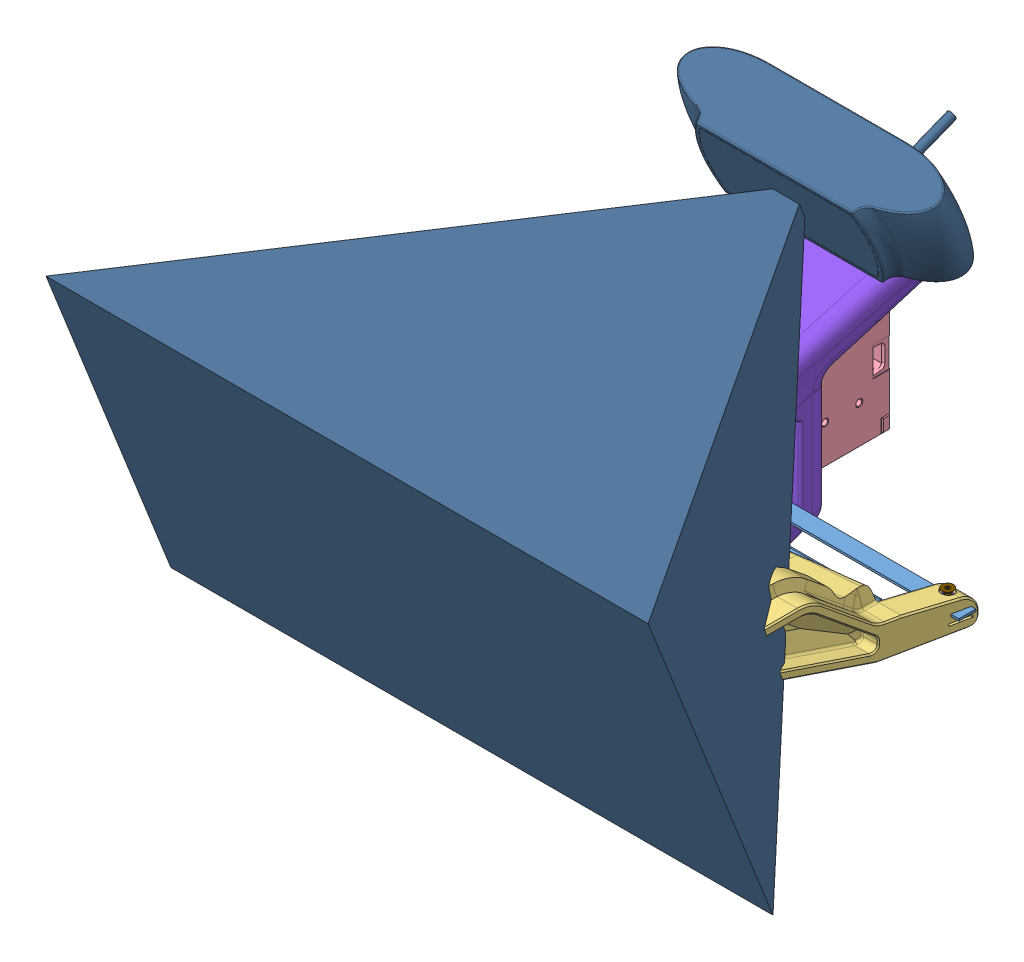
SolidWorks assembly OpenGrip_Assy, configuration Default. Lengths in mm.
Overall size (168.5 132.23 164.7).
65 component instances, 20 part files, 137 mates.
Components (placement in the parent):
- OpenGrip_Master-2: OpenGrip_Master [Default] at origin (suppressed, hidden)
- MGN7_Rail-1: MGN7_Rail [80mm] at (21.75 9 42.45) x (0 1 0) z (-1 0 0) size (7 4.8 80)
- MGN7_Rail-2: MGN7_Rail [80mm] at (78.25 -9 42.45) x (0 1 0) z (-1 0 0) size (7 4.8 80)
- MGN7C_Carriage-1: MGN7C_Carriage [Default] at (0 9 40) x (0 -1 0) z (1 0 0) size (17 6.5 23.48)
- MGN7C_Carriage-2: MGN7C_Carriage [Default] at (0 -9 40) x (0 -1 0) z (1 0 0) size (17 6.5 23.48)
- Gripper_Jaw-1: Gripper_Jaw [Default] at (0 0 0.1) size (101.38 32.39 102.84)
- Gripper_Jaw-2: Gripper_Jaw [Default] at (0 0 0.1) x (-1 0 0) z (0 0 1) size (101.38 32.39 102.84)
- XL-430-1: XL-430 [Default] x (-1 0 0) z (0 0 1) size (28.5 46.5 34)
- 430_Horn-1: 430_Horn [Default] at (0 0 0.25) x (-0.999988 0.004902 0) z (0 0 1) size (20.5 20.5 4.15)
- Gripper_Carriage_Mount-1: Gripper_Carriage_Mount [Default] at origin size (34.5 55.1 3.17)
- Gripper_Drive_Pulley-1: Gripper_Drive_Pulley [Default] x (-0.999864 -0.016494 0) z (0 0 1) size (27 27 12.75)
- Gripper_Structure-1: Gripper_Structure [Default] at origin size (59.8 80.24 58.54)
- CF_Spring_Idler-1: CF_Spring_Idler [Default] at (-19.402 17.1492 0) x (0.122802 -0.992431 0) z (0 0 1) size (9.1 9.1 8.94)
- CF_Spring_Idler-2: CF_Spring_Idler [Default] at (-7.4466 -37.6262 0) x (0.924615 -0.380902 0) z (0 0 1) size (9.1 9.1 8.94)
- C922X_Pro-1: C922X_Pro [Tilted Down] at (-0.0197 67.744 0.4358) x (1 0 0) z (0 0.110801 0.993843) size (211.74 160.55 195.68)
- CF_Spring_Idler_Cap-1: CF_Spring_Idler_Cap [Default] at origin size (9.1 9.1 1)
- CF_Spring_Idler_Cap-2: CF_Spring_Idler_Cap [Default] at (0 -39.1 0) size (9.1 9.1 1)
- 0.1x8x110_CF-2: 0.1x8x110_CF [9293K111] at (0 -19.55 28.4812) x (0 0 1) z (0 1 0) size (8.01 10.11 7.57)
- 0.1x8x110_CF-1: 0.1x8x110_CF [9293K111] at (0 19.55 28.4812) x (0 0 1) z (0 -1 0) size (8.01 10.11 7.57)
- 91292A831_18-8 Stainless Steel Socket Head Screw-1: 91292A831_18-8 Stainless Steel Socket Head Screw [91292A831] at (58.25 -9 48.35) x (-0.599094 -0.800678 0) z (0 0 1) size (3.8 3.8 8.1)
- 92125A051_18-8 Stainless Steel Hex Drive Flat Head Screw-1: 92125A051_18-8 Stainless Steel Hex Drive Flat Head Screw [92125A051] at (-4 15 36.215) x (-1 0 0) z (0 0 -1) size (4 4 5.21)
- 92125A059_18-8 Stainless Steel Hex Drive Flat Head Screw-1: 92125A059_18-8 Stainless Steel Hex Drive Flat Head Screw [92125A059] at (0 19.55 28.61) size (4 4 16.28)
- 92125A059_18-8 Stainless Steel Hex Drive Flat Head Screw-2: 92125A059_18-8 Stainless Steel Hex Drive Flat Head Screw [92125A059] at (0 -19.55 28.61) x (0.987351 0.158553 0) z (0 0 1) size (4 4 16.28)
- 92000A108_Passivated 18-8 Stainless Steel Pan Head Phillips Screws-1: 92000A108_Passivated 18-8 Stainless Steel Pan Head Phillips Screws [92000A108] at (-11 32 12.45) x (0.327132 -0.944979 0) z (0 0 1) size (5 5 16.27)
- 92000A108_Passivated 18-8 Stainless Steel Pan Head Phillips Screws-2: 92000A108_Passivated 18-8 Stainless Steel Pan Head Phillips Screws [92000A108] at (11 32 12.45) x (-0.176447 -0.98431 0) z (0 0 1) size (5 5 16.27)
- 92000A108_Passivated 18-8 Stainless Steel Pan Head Phillips Screws-4: 92000A108_Passivated 18-8 Stainless Steel Pan Head Phillips Screws [92000A108] at (-11 -8 12.45) x (-0.17128 0.985222 0) z (0 0 1) size (5 5 16.27)
- 92000A108_Passivated 18-8 Stainless Steel Pan Head Phillips Screws-6: 92000A108_Passivated 18-8 Stainless Steel Pan Head Phillips Screws [92000A108] at (11.1653 -8.1875 12.45) x (-0.186548 -0.982446 0) z (0 0 1) size (5 5 16.27)
- M2_Heatset-1: M2_Heatset [94180A307] at (-1.75 -9 46.31) x (-0.923728 -0.383049 0) z (0 0 -1) size (3.58 3.58 3.07)
- M2_Heatset-2: M2_Heatset [94180A307] at (13.25 -9 46.31) x (-0.85131 -0.524663 0) z (0 0 -1) size (3.58 3.58 3.07)
- M2_Heatset-3: M2_Heatset [94180A307] at (28.25 -9 46.31) x (-0.777574 -0.628792 0) z (0 0 -1) size (3.58 3.58 3.07)
- M2_Heatset-4: M2_Heatset [94180A307] at (43.25 -9 46.31) x (-0.715577 -0.698533 0) z (0 0 -1) size (3.58 3.58 3.07)
- M2_Heatset-5: M2_Heatset [94180A307] at (58.25 -9 46.31) x (-0.676489 -0.736453 0) z (0 0 -1) size (3.58 3.58 3.07)
- M2_Heatset-8: M2_Heatset [94180A307] at (-58.25 9 46.31) x (-0.669293 -0.742999 0) z (0 0 -1) size (3.58 3.58 3.07)
- M2_Heatset-10: M2_Heatset [94180A307] at (-43.25 9 46.31) x (-0.699005 -0.715117 0) z (0 0 -1) size (3.58 3.58 3.07)
- M2_Heatset-12: M2_Heatset [94180A307] at (-28.25 9 46.31) x (-0.762825 -0.646605 0) z (0 0 -1) size (3.58 3.58 3.07)
- M2_Heatset-14: M2_Heatset [94180A307] at (-13.25 9 46.31) x (-0.845962 -0.533243 0) z (0 0 -1) size (3.58 3.58 3.07)
- M2_Heatset-16: M2_Heatset [94180A307] at (1.75 9 46.31) x (-0.923728 -0.383049 0) z (0 0 -1) size (3.58 3.58 3.07)
- 91292A831_18-8 Stainless Steel Socket Head Screw-3: 91292A831_18-8 Stainless Steel Socket Head Screw [91292A831] at (43.25 -9 48.35) x (0.684483 -0.729029 0) z (0 0 1) size (3.8 3.8 8.1)
- 91292A831_18-8 Stainless Steel Socket Head Screw-5: 91292A831_18-8 Stainless Steel Socket Head Screw [91292A831] at (28.25 -9 48.35) x (0.547489 -0.836813 0) z (0 0 1) size (3.8 3.8 8.1)
- 91292A831_18-8 Stainless Steel Socket Head Screw-7: 91292A831_18-8 Stainless Steel Socket Head Screw [91292A831] at (13.25 -9 48.35) x (0.393861 -0.91917 0) z (0 0 1) size (3.8 3.8 8.1)
- 91292A831_18-8 Stainless Steel Socket Head Screw-9: 91292A831_18-8 Stainless Steel Socket Head Screw [91292A831] at (-1.75 -9 48.35) x (0.228265 -0.973599 0) z (0 0 1) size (3.8 3.8 8.1)
- 91292A831_18-8 Stainless Steel Socket Head Screw-11: 91292A831_18-8 Stainless Steel Socket Head Screw [91292A831] at (1.75 9 48.35) x (0.055733 -0.998446 0) z (0 0 1) size (3.8 3.8 8.1)
- 91292A831_18-8 Stainless Steel Socket Head Screw-13: 91292A831_18-8 Stainless Steel Socket Head Screw [91292A831] at (-13.25 9 48.35) x (-0.118492 -0.992955 0) z (0 0 1) size (3.8 3.8 8.1)
- 91292A831_18-8 Stainless Steel Socket Head Screw-15: 91292A831_18-8 Stainless Steel Socket Head Screw [91292A831] at (-28.25 9 48.35) x (-0.289116 -0.957294 0) z (0 0 1) size (3.8 3.8 8.1)
- 91292A831_18-8 Stainless Steel Socket Head Screw-17: 91292A831_18-8 Stainless Steel Socket Head Screw [91292A831] at (-43.25 9 48.35) x (-0.450956 -0.892546 0) z (0 0 1) size (3.8 3.8 8.1)
- 91292A831_18-8 Stainless Steel Socket Head Screw-19: 91292A831_18-8 Stainless Steel Socket Head Screw [91292A831] at (-58.25 9 48.35) x (-0.599094 -0.800678 0) z (0 0 1) size (3.8 3.8 8.1)
- M2_Heatset-18: M2_Heatset [94180A307] at (-77.9377 7.46 26.6) x (0.982823 0 0.184551) z (0 -1 0) size (3.58 3.58 3.07)
- 92125A054_18-8 Stainless Steel Hex Drive Flat Head Screw-1: 92125A054_18-8 Stainless Steel Hex Drive Flat Head Screw [92125A054] at (-77.9377 8.125 26.6) x (1 0 0) z (0 -1 0) size (4 4 8.23)
- M2_Heatset-19: M2_Heatset [94180A307] at (77.9377 -7.46 26.6) x (0.184551 0 0.982823) z (0 1 0) size (3.58 3.58 3.07)
- 92125A054_18-8 Stainless Steel Hex Drive Flat Head Screw-2: 92125A054_18-8 Stainless Steel Hex Drive Flat Head Screw [92125A054] at (77.9377 -8.125 26.6) x (0 0 1) z (0 1 0) size (4 4 8.23)
- M2_Heatset-21: M2_Heatset [94180A307] at (14.75 13.04 28.5813) x (0.366462 0 0.930433) z (0 1 0) size (3.58 3.58 3.07)
- 92125A054_18-8 Stainless Steel Hex Drive Flat Head Screw-4: 92125A054_18-8 Stainless Steel Hex Drive Flat Head Screw [92125A054] at (14.75 11.5 28.5813) x (0 0 1) z (0 1 0) size (4 4 8.23)
- M2_Heatset-23: M2_Heatset [94180A307] at (-14.75 -13.04 28.5813) x (0.930433 0 0.366462) z (0 -1 0) size (3.58 3.58 3.07)
- 92125A054_18-8 Stainless Steel Hex Drive Flat Head Screw-5: 92125A054_18-8 Stainless Steel Hex Drive Flat Head Screw [92125A054] at (-14.75 -11.5 28.5813) x (1 0 0) z (0 -1 0) size (4 4 8.23)
- 92125A054_18-8 Stainless Steel Hex Drive Flat Head Screw-7: 92125A054_18-8 Stainless Steel Hex Drive Flat Head Screw [92125A054] at (-12.25 22.55 32.61) x (0 -1 0) z (0 0 1) size (4 4 8.23)
- M2_Heatset-25: M2_Heatset [94180A307] at (0 -19.55 21.9275) x (-0.719094 -0.694913 0) z (0 0 1) size (3.58 3.58 3.07)
- M2_Heatset-26: M2_Heatset [94180A307] at (-12.25 -22.55 32.115) x (-0.599818 -0.800137 0) z (0 0 1) size (3.58 3.58 3.07)
- M2_Heatset-28: M2_Heatset [94180A307] at (12.25 -22.55 32.115) x (-0.493052 -0.87 0) z (0 0 1) size (3.58 3.58 3.07)
- M2_Heatset-30: M2_Heatset [94180A307] at (0 19.55 21.9275) x (-0.409811 -0.91217 0) z (0 0 1) size (3.58 3.58 3.07)
- M2_Heatset-32: M2_Heatset [94180A307] at (-12.25 22.55 32.115) x (-0.359546 -0.933127 0) z (0 0 1) size (3.58 3.58 3.07)
- M2_Heatset-34: M2_Heatset [94180A307] at (12.25 22.55 32.115) x (-0.350452 -0.936581 0) z (0 0 1) size (3.58 3.58 3.07)
- 92125A054_18-8 Stainless Steel Hex Drive Flat Head Screw-8: 92125A054_18-8 Stainless Steel Hex Drive Flat Head Screw [92125A054] at (12.25 22.55 32.61) x (0.158553 -0.987351 0) z (0 0 1) size (4 4 8.23)
- 92125A054_18-8 Stainless Steel Hex Drive Flat Head Screw-10: 92125A054_18-8 Stainless Steel Hex Drive Flat Head Screw [92125A054] at (12.25 -22.55 32.61) x (0.282984 -0.959125 0) z (0 0 1) size (4 4 8.23)
- 92125A054_18-8 Stainless Steel Hex Drive Flat Head Screw-12: 92125A054_18-8 Stainless Steel Hex Drive Flat Head Screw [92125A054] at (-12.25 -22.55 32.61) x (0.371154 -0.928571 0) z (0 0 1) size (4 4 8.23)
- Drive Belt-1: Drive Belt [Default] at (1.3318 1.3765 0.1) x (0.999864 0.016494 0) z (0 0 1) size (166.7 24.25 6)
Mates (geometry in assembly coordinates):
- Width1: width anti-aligned: plane of MGN7C_Carriage-1 through (6.75 12.5 40) normal (0 -1 0); plane of MGN7_Rail-1 through (6.75 5.5 40) normal (0 1 0); plane of MGN7C_Carriage-1 through (-78.25 12.5 40.7563) normal (0 1 0); plane of MGN7_Rail-1 through (-78.25 5.5 40.7563) normal (0 -1 0)
- Coincident7: coincident anti-aligned: plane of MGN7_Rail-1 through (-78.25 5.7 40.05) normal (0 0 -1); plane of MGN7C_Carriage-1 through (6.75 9 40.05) normal (0 0 1)
- Coincident8: coincident: line of OpenGrip_Master-2 through (-11.25 17.5 36.75) axis (0 -1 0); plane of MGN7C_Carriage-1 through (-11.25 9 40) normal (-1 0 0)
- Coincident9: coincident anti-aligned: plane of OpenGrip_Master-2 through (0 0 36.75) normal (0 0 1); plane of MGN7C_Carriage-1 through (6.75 9 36.75) normal (0 0 -1)
- Coincident11: coincident: line of OpenGrip_Master-2 through (11.25 17.5 36.75) axis (-1 0 0); plane of MGN7C_Carriage-1 through (6.75 17.5 40) normal (0 1 0)
- Coincident12: coincident: line of OpenGrip_Master-2 through (-11.25 -17.5 36.75) axis (1 0 0); plane of MGN7C_Carriage-2 through (6.75 -17.5 40) normal (0 -1 0)
- Coincident13: coincident: line of OpenGrip_Master-2 through (11.25 -0.5 36.75) axis (0 -1 0); plane of MGN7C_Carriage-2 through (11.25 -9 40) normal (1 0 0)
- Coincident14: coincident anti-aligned: plane of OpenGrip_Master-2 through (0 0 36.75) normal (0 0 1); plane of MGN7C_Carriage-2 through (6.75 -9 36.75) normal (0 0 -1)
- Coincident15: coincident anti-aligned: plane of MGN7_Rail-2 through (-21.75 -12.3 40.05) normal (0 0 -1); plane of MGN7C_Carriage-2 through (6.75 -9 40.05) normal (0 0 1)
- Width2: width anti-aligned: plane of MGN7_Rail-2 through (-21.75 -12.5 40.7563) normal (0 -1 0); plane of MGN7C_Carriage-2 through (-21.75 -5.5 40.7563) normal (0 1 0); plane of MGN7_Rail-2 through (6.75 -12.5 40) normal (0 1 0); plane of MGN7C_Carriage-2 through (6.75 -5.5 40) normal (0 -1 0)
- Linear/Linear Coupler1: linear coupler = 0.001 : 0.001 mm: plane of MGN7_Rail-1 through (-68.25 5.5 44.85) normal (-1 0 0); plane of MGN7_Rail-2 through (68.25 -12.5 44.85) normal (1 0 0)
- Coincident35: coincident anti-aligned: plane of MGN7_Rail-1 through (11.75 5.5 44.85) normal (1 0 0); plane of Gripper_Jaw-1 through (11.75 0 31.32) normal (-1 0 0)
- Coincident36: coincident anti-aligned: plane of MGN7_Rail-1 through (-78.25 5.7 44.85) normal (0 0 1); plane of Gripper_Jaw-1 through (-69 0 44.85) normal (0 0 -1)
- Coincident37: coincident anti-aligned: plane of MGN7_Rail-2 through (-11.75 -12.5 44.85) normal (-1 0 0); plane of Gripper_Jaw-2 through (-11.75 0 31.32) normal (1 0 0)
- Coincident38: coincident anti-aligned: plane of MGN7_Rail-2 through (-21.75 -12.3 44.85) normal (0 0 1); plane of Gripper_Jaw-2 through (69 0 44.85) normal (0 0 -1)
- Concentric3: concentric anti-aligned: line of XL-430-1 through (0 0 18.8501) axis (0 0 -1); cylinder of 430_Horn-1 through (0 0 15.75) axis (0 0 1) radius 10.25
- Coincident39: coincident anti-aligned: plane of XL-430-1 through (0 0 17) normal (0 0 1); plane of 430_Horn-1 through (10.9766 -4.8039 17) normal (0 0 -1)
- Coincident40: coincident anti-aligned: line of OpenGrip_Master-2 through (0 0 -215.0809) axis (0 0 1); line of XL-430-1 through (0 0 18.8501) axis (0 0 -1)
- Concentric4: concentric aligned: cylinder of CF_Spring_Idler-1 through (0 19.55 33.45) axis (0 0 1) radius 2.8; circle of 0.1x8x110_CF-1
- Width5: width aligned: plane of 0.1x8x110_CF-1 through (0.514 16.635 32.4813) normal (0 0 1); plane of CF_Spring_Idler-1 through (0.514 16.635 24.4812) normal (0 0 -1); plane of 0.1x8x110_CF-1 through (-19.402 17.1492 33.45) normal (0 0 1); plane of CF_Spring_Idler_Cap-1 through (0 0 23.5125) normal (0 0 -1)
- Concentric7: concentric aligned: cylinder of MGN7_Rail-1 through (-58.25 9 44.851) axis (0 0 -1) radius 1.2; cylinder of Gripper_Jaw-1 through (-58.25 9 55.2341) axis (0 0 -1) radius 1.55
- Coincident42: coincident anti-aligned: plane of MGN7C_Carriage-1 through (6.75 9 36.75) normal (0 0 -1); plane of Gripper_Carriage_Mount-1 through (0 0 36.75) normal (0 0 1)
- Concentric8: concentric aligned: cylinder of MGN7C_Carriage-1 through (4 15 36.75) axis (0 0 -1) radius 0.8; cylinder of Gripper_Carriage_Mount-1 through (4 15 33.575) axis (0 0 -1) radius 1.1
- Concentric9: concentric aligned: cylinder of MGN7C_Carriage-1 through (-4 15 36.75) axis (0 0 -1) radius 0.8; cylinder of Gripper_Carriage_Mount-1 through (-4 15 33.575) axis (0 0 -1) radius 1.1
- Concentric11: concentric aligned: cylinder of Gripper_Carriage_Mount-1 through (0 19.55 36.75) axis (0 0 1) radius 1.1; cylinder of Gripper_Structure-1 through (0 19.55 19.3875) axis (0 0 1) radius 1.65
- Concentric12: concentric aligned: cylinder of Gripper_Carriage_Mount-1 through (0 -19.55 36.75) axis (0 0 1) radius 1.1; cylinder of Gripper_Structure-1 through (0 -19.55 19.3875) axis (0 0 1) radius 1.65
- Concentric13: concentric aligned: cylinder of Gripper_Carriage_Mount-1 through (0 19.55 36.75) axis (0 0 1) radius 1.1; cylinder of CF_Spring_Idler-1 through (0 19.55 33.45) axis (0 0 1) radius 1.1
- Concentric14: concentric aligned: cylinder of Gripper_Carriage_Mount-1 through (0 -19.55 36.75) axis (0 0 1) radius 1.1; cylinder of CF_Spring_Idler-2 through (0 -19.55 33.45) axis (0 0 1) radius 1.1
- Concentric15: concentric aligned: cylinder of MGN7_Rail-2 through (58.25 -9 44.851) axis (0 0 -1) radius 1.2; cylinder of Gripper_Jaw-2 through (58.25 -9 55.2341) axis (0 0 -1) radius 1.55
- LimitDistance2: limit distance = 57 mm aligned: plane of MGN7_Rail-2 through (68.25 -12.5 44.85) normal (1 0 0); plane of MGN7C_Carriage-2 through (11.25 -9 40) normal (1 0 0)
- Coincident47: coincident aligned: cone of Gripper_Structure-1 through (-11 8 20.5) axis (0 0 -1); cone of 92010A775_Passivated 18-8 Stainless Steel Phillips Flat Head Screw-1 through (-11 8 19.05) axis (0 0 -1)
- Coincident48: coincident aligned: cone of Gripper_Carriage_Mount-1 through (-4 15 33.575) axis (0 0 1); cone of 92125A051_18-8 Stainless Steel Hex Drive Flat Head Screw-1 through (-4 15 33.775) axis (0 0 1)
- Concentric17: concentric aligned: circle of MGN7_Rail-2; circle of 91292A831_18-8 Stainless Steel Socket Head Screw-1
- Coincident49: coincident anti-aligned: plane of MGN7_Rail-2 through (58.25 -9 42.35) normal (0 0 -1); plane of 91292A831_18-8 Stainless Steel Socket Head Screw-1 through (58.25 -9 42.35) normal (0 0 1)
- Coincident50: coincident aligned: cone of Gripper_Carriage_Mount-1 through (0 19.55 36.75) axis (0 0 -1); cone of 92125A059_18-8 Stainless Steel Hex Drive Flat Head Screw-1 through (0 19.55 36.55) axis (0 0 -1)
- Coincident55: coincident aligned: cone of Gripper_Structure-1 through (11 8 20.5) axis (0 0 -1); cone of 92010A775_Passivated 18-8 Stainless Steel Phillips Flat Head Screw-2 through (11 8 19.05) axis (0 0 -1)
- Coincident56: coincident aligned: cone of Gripper_Carriage_Mount-1 through (0 -19.55 36.75) axis (0 0 -1); cone of 92125A059_18-8 Stainless Steel Hex Drive Flat Head Screw-2 through (0 -19.55 36.55) axis (0 0 -1)
- Concentric22: concentric anti-aligned: cylinder of 430_Horn-1 through (0 0 19.25) axis (0 0 1) radius 4; cylinder of Gripper_Drive_Pulley-1 through (0 0 -215.0809) axis (0 0 -1) radius 10
- Coincident61: coincident anti-aligned: plane of 430_Horn-1 through (0 0 19.25) normal (0 0 1); plane of Gripper_Drive_Pulley-1 through (0 0 19.25) normal (0 0 -1)
- Concentric23: concentric aligned: cylinder of XL-430-1 through (-11 32 12.38) axis (0 0 1) radius 1.3; cylinder of Gripper_Structure-1 through (-11 32 20.5) axis (0 0 1) radius 2.75
- Concentric24: concentric aligned: circle of Gripper_Structure-1; circle of 92000A108_Passivated 18-8 Stainless Steel Pan Head Phillips Screws-1
- Coincident63: coincident anti-aligned: plane of Gripper_Structure-1 through (-9.65 32 18.4) normal (0 0 1); plane of 92000A108_Passivated 18-8 Stainless Steel Pan Head Phillips Screws-1 through (-12.7968 31.378 18.4) normal (0 0 -1)
- Concentric25: concentric aligned: circle of 92000A108_Passivated 18-8 Stainless Steel Pan Head Phillips Screws-2; cylinder of Gripper_Structure-1 through (11 32 20.5) axis (0 0 1) radius 1.35
- Coincident64: coincident anti-aligned: plane of Gripper_Structure-1 through (9.65 32 18.4) normal (0 0 1); plane of 92000A108_Passivated 18-8 Stainless Steel Pan Head Phillips Screws-2 through (9.1284 32.3355 18.4) normal (0 0 -1)
- Concentric26: concentric aligned: circle of Gripper_Structure-1; circle of 92000A108_Passivated 18-8 Stainless Steel Pan Head Phillips Screws-4
- Coincident65: coincident anti-aligned: plane of Gripper_Structure-1 through (-9.65 -8 18.4) normal (0 0 1); plane of 92000A108_Passivated 18-8 Stainless Steel Pan Head Phillips Screws-4 through (-9.1266 -7.6743 18.4) normal (0 0 -1)
- Concentric28: concentric aligned: cylinder of Gripper_Structure-1 through (-25.869 104.5877 -24.8422) axis (0 -0.993843 0.110801) radius 1.1; cylinder of C922X_Pro-1 through (-25.869 56.5923 -19.4913) axis (0 -0.993843 0.110801) radius 1.65
- Parallel3: parallel aligned: plane of C922X_Pro-1 through (-0.0197 67.744 0.4358) normal (1 0 0)
- Coincident68: coincident anti-aligned: plane of XL-430-1 through (0 0 17) normal (0 0 1); plane of Gripper_Structure-1 through (0 0 17) normal (0 0 -1)
- Coincident69: coincident anti-aligned: plane of Gripper_Structure-1 through (-53.7853 52.1598 -5.0985) normal (0 0.993843 -0.110801); plane of C922X_Pro-1 through (29.48 49.9645 -24.7896) normal (0 -0.993843 0.110801)
- Tangent1: tangent aligned: cylinder of Gripper_Structure-1 through (11 -8 20.5) axis (0 0 1) radius 2.75; torus of 92000A108_Passivated 18-8 Stainless Steel Pan Head Phillips Screws-6
- Coincident70: coincident anti-aligned: plane of Gripper_Structure-1 through (9.65 -8 18.4) normal (0 0 1); plane of 92000A108_Passivated 18-8 Stainless Steel Pan Head Phillips Screws-6 through (9.2972 -7.8328 18.4) normal (0 0 -1)
- Coincident74: coincident anti-aligned: plane of Gripper_Carriage_Mount-1 through (0 0 33.575) normal (0 0 -1); plane of Gripper_Structure-1 through (0 0 33.575) normal (0 0 1)
- Parallel5: parallel: line of 0.1x8x110_CF-1 through (2 15.6473 28.4812) axis (1 0 0)
- Concentric29: concentric aligned: cylinder of CF_Spring_Idler-2 through (0 -19.55 33.45) axis (0 0 1) radius 2.8; circle of 0.1x8x110_CF-2
- Width6: width aligned: plane of 0.1x8x110_CF-2 through (-0.514 -16.635 24.4812) normal (0 0 -1); plane of 0.1x8x110_CF-2 through (-0.514 -16.635 32.4813) normal (0 0 1); plane of CF_Spring_Idler_Cap-2 through (0 -39.1 23.5125) normal (0 0 -1); plane of CF_Spring_Idler-2 through (-7.4466 -37.6262 33.45) normal (0 0 1)
- Parallel6: parallel: line of 0.1x8x110_CF-2 through (-2 -15.6473 28.4812) axis (-1 0 0)
- Coincident75: coincident anti-aligned: plane of CF_Spring_Idler-2 through (-7.4466 -37.6262 24.5125) normal (0 0 -1); plane of CF_Spring_Idler_Cap-2 through (0 -39.1 24.5125) normal (0 0 1)
- Width7: width anti-aligned: plane of CF_Spring_Idler-2 through (-7.4466 -37.6262 33.45) normal (0 0 1); plane of CF_Spring_Idler_Cap-2 through (0 -39.1 23.5125) normal (0 0 -1); plane of Gripper_Carriage_Mount-1 through (0 0 33.575) normal (0 0 -1); plane of Gripper_Structure-1 through (0 -19.55 23.3875) normal (0 0 1)
- Coincident76: coincident anti-aligned: plane of CF_Spring_Idler-1 through (-19.402 17.1492 24.5125) normal (0 0 -1); plane of CF_Spring_Idler_Cap-1 through (0 0 24.5125) normal (0 0 1)
- Width8: width anti-aligned: plane of CF_Spring_Idler-1 through (-19.402 17.1492 33.45) normal (0 0 1); plane of CF_Spring_Idler_Cap-1 through (0 0 23.5125) normal (0 0 -1); plane of Gripper_Carriage_Mount-1 through (0 0 33.575) normal (0 0 -1); plane of Gripper_Structure-1 through (0 19.55 23.3875) normal (0 0 1)
- Concentric30: concentric aligned: cylinder of Gripper_Structure-1 through (0 19.55 19.3875) axis (0 0 1) radius 1.65; cylinder of CF_Spring_Idler_Cap-1 through (0 19.55 33.45) axis (0 0 1) radius 1.1
- Concentric31: concentric aligned: cylinder of Gripper_Structure-1 through (0 -19.55 19.3875) axis (0 0 1) radius 1.65; cylinder of CF_Spring_Idler_Cap-2 through (0 -19.55 33.45) axis (0 0 1) radius 1.1
- Concentric32: concentric aligned: cylinder of Gripper_Jaw-2 through (-1.75 -9 55.2341) axis (0 0 -1) radius 1.55; cylinder of M2_Heatset-1 through (-1.75 -9 44.85) axis (0 0 -1) radius 1.395
- Coincident77: coincident aligned: plane of Gripper_Jaw-2 through (69 0 44.85) normal (0 0 -1); plane of M2_Heatset-1 through (-2.133 -8.0763 44.85) normal (0 0 -1)
- Coincident78: coincident aligned: plane of Gripper_Jaw-2 through (69 0 44.85) normal (0 0 -1); plane of M2_Heatset-2 through (12.7253 -8.1487 44.85) normal (0 0 -1)
- Concentric33: concentric aligned: cylinder of Gripper_Jaw-2 through (13.25 -9 55.2341) axis (0 0 -1) radius 1.55; cylinder of M2_Heatset-2 through (13.25 -9 44.85) axis (0 0 -1) radius 1.395
- Coincident79: coincident aligned: plane of Gripper_Jaw-2 through (69 0 44.85) normal (0 0 -1); plane of M2_Heatset-3 through (27.6212 -8.2224 44.85) normal (0 0 -1)
- Concentric34: concentric aligned: cylinder of Gripper_Jaw-2 through (28.25 -9 55.2341) axis (0 0 -1) radius 1.55; cylinder of M2_Heatset-3 through (28.25 -9 44.85) axis (0 0 -1) radius 1.395
- Coincident80: coincident aligned: plane of Gripper_Jaw-2 through (69 0 44.85) normal (0 0 -1); plane of M2_Heatset-4 through (42.5515 -8.2844 44.85) normal (0 0 -1)
- Concentric35: concentric aligned: cylinder of Gripper_Jaw-2 through (43.25 -9 55.2341) axis (0 0 -1) radius 1.55; cylinder of M2_Heatset-4 through (43.25 -9 44.85) axis (0 0 -1) radius 1.395
- Coincident81: coincident aligned: plane of Gripper_Jaw-2 through (69 0 44.85) normal (0 0 -1); plane of M2_Heatset-5 through (57.5135 -8.3235 44.85) normal (0 0 -1)
- Concentric36: concentric aligned: cylinder of Gripper_Jaw-2 through (58.25 -9 55.2341) axis (0 0 -1) radius 1.55; cylinder of M2_Heatset-5 through (58.25 -9 44.85) axis (0 0 -1) radius 1.395
- Coincident83: coincident aligned: plane of Gripper_Jaw-1 through (-69 0 44.85) normal (0 0 -1); plane of M2_Heatset-8 through (-58.993 9.6693 44.85) normal (0 0 -1)
- Concentric37: concentric aligned: cylinder of Gripper_Jaw-1 through (-58.25 9 55.2341) axis (0 0 -1) radius 1.55; cylinder of M2_Heatset-8 through (-58.25 9 44.85) axis (0 0 -1) radius 1.395
- Concentric38: concentric aligned: cylinder of Gripper_Jaw-1 through (-43.25 9 55.2341) axis (0 0 -1) radius 1.55; cylinder of M2_Heatset-10 through (-43.25 9 44.85) axis (0 0 -1) radius 1.395
- Coincident84: coincident aligned: plane of Gripper_Jaw-1 through (-69 0 44.85) normal (0 0 -1); plane of M2_Heatset-10 through (-43.9651 9.699 44.85) normal (0 0 -1)
- Concentric39: concentric aligned: cylinder of Gripper_Jaw-1 through (-28.25 9 55.2341) axis (0 0 -1) radius 1.55; cylinder of M2_Heatset-12 through (-28.25 9 44.85) axis (0 0 -1) radius 1.395
- Coincident85: coincident aligned: plane of Gripper_Jaw-1 through (-69 0 44.85) normal (0 0 -1); plane of M2_Heatset-12 through (-28.8966 9.7628 44.85) normal (0 0 -1)
- Concentric40: concentric aligned: cylinder of Gripper_Jaw-1 through (-13.25 9 55.2341) axis (0 0 -1) radius 1.55; cylinder of M2_Heatset-14 through (-13.25 9 44.85) axis (0 0 -1) radius 1.395
- Coincident86: coincident aligned: plane of Gripper_Jaw-1 through (-69 0 44.85) normal (0 0 -1); plane of M2_Heatset-14 through (-13.7832 9.846 44.85) normal (0 0 -1)
- Concentric41: concentric aligned: cylinder of Gripper_Jaw-1 through (1.75 9 55.2341) axis (0 0 -1) radius 1.55; cylinder of M2_Heatset-16 through (1.75 9 44.85) axis (0 0 -1) radius 1.395
- Coincident87: coincident aligned: plane of Gripper_Jaw-1 through (-69 0 44.85) normal (0 0 -1); plane of M2_Heatset-16 through (1.367 9.9237 44.85) normal (0 0 -1)
- Concentric43: concentric anti-aligned: cylinder of MGN7_Rail-2 through (43.25 -9 42.35) axis (0 0 -1) radius 2.1; circle of 91292A831_18-8 Stainless Steel Socket Head Screw-3
- Coincident89: coincident anti-aligned: plane of MGN7_Rail-2 through (43.25 -9 42.35) normal (0 0 -1); plane of 91292A831_18-8 Stainless Steel Socket Head Screw-3 through (43.25 -9 42.35) normal (0 0 1)
- Concentric44: concentric anti-aligned: cylinder of MGN7_Rail-2 through (28.25 -9 42.35) axis (0 0 -1) radius 2.1; circle of 91292A831_18-8 Stainless Steel Socket Head Screw-5
- Coincident90: coincident anti-aligned: plane of MGN7_Rail-2 through (28.25 -9 42.35) normal (0 0 -1); plane of 91292A831_18-8 Stainless Steel Socket Head Screw-5 through (28.25 -9 42.35) normal (0 0 1)
- Concentric45: concentric anti-aligned: cylinder of MGN7_Rail-2 through (13.25 -9 42.35) axis (0 0 -1) radius 2.1; circle of 91292A831_18-8 Stainless Steel Socket Head Screw-7
- Coincident92: coincident anti-aligned: plane of MGN7_Rail-2 through (13.25 -9 42.35) normal (0 0 -1); plane of 91292A831_18-8 Stainless Steel Socket Head Screw-7 through (13.25 -9 42.35) normal (0 0 1)
- Concentric46: concentric anti-aligned: cylinder of MGN7_Rail-2 through (-1.75 -9 42.35) axis (0 0 -1) radius 2.1; circle of 91292A831_18-8 Stainless Steel Socket Head Screw-9
- Concentric47: concentric anti-aligned: cylinder of MGN7_Rail-1 through (1.75 9 42.35) axis (0 0 -1) radius 2.1; circle of 91292A831_18-8 Stainless Steel Socket Head Screw-11
- Coincident96: coincident anti-aligned: plane of MGN7_Rail-1 through (1.75 9 42.35) normal (0 0 -1); plane of 91292A831_18-8 Stainless Steel Socket Head Screw-11 through (1.75 9 42.35) normal (0 0 1)
- Concentric48: concentric anti-aligned: cylinder of MGN7_Rail-1 through (-13.25 9 42.35) axis (0 0 -1) radius 2.1; circle of 91292A831_18-8 Stainless Steel Socket Head Screw-13
- Coincident98: coincident anti-aligned: plane of MGN7_Rail-1 through (-13.25 9 42.35) normal (0 0 -1); plane of 91292A831_18-8 Stainless Steel Socket Head Screw-13 through (-13.25 9 42.35) normal (0 0 1)
- Concentric49: concentric anti-aligned: cylinder of MGN7_Rail-1 through (-28.25 9 42.35) axis (0 0 -1) radius 2.1; circle of 91292A831_18-8 Stainless Steel Socket Head Screw-15
- Coincident100: coincident anti-aligned: plane of MGN7_Rail-1 through (-28.25 9 42.35) normal (0 0 -1); plane of 91292A831_18-8 Stainless Steel Socket Head Screw-15 through (-28.25 9 42.35) normal (0 0 1)
- Concentric50: concentric anti-aligned: cylinder of MGN7_Rail-1 through (-43.25 9 42.35) axis (0 0 -1) radius 2.1; circle of 91292A831_18-8 Stainless Steel Socket Head Screw-17
- Coincident101: coincident anti-aligned: plane of MGN7_Rail-1 through (-43.25 9 42.35) normal (0 0 -1); plane of 91292A831_18-8 Stainless Steel Socket Head Screw-17 through (-43.25 9 42.35) normal (0 0 1)
- Concentric51: concentric anti-aligned: cylinder of MGN7_Rail-1 through (-58.25 9 42.35) axis (0 0 -1) radius 2.1; circle of 91292A831_18-8 Stainless Steel Socket Head Screw-19
- Coincident102: coincident anti-aligned: plane of MGN7_Rail-1 through (-58.25 9 42.35) normal (0 0 -1); plane of 91292A831_18-8 Stainless Steel Socket Head Screw-19 through (-58.25 9 42.35) normal (0 0 1)
- Concentric52: concentric aligned: cylinder of Gripper_Jaw-1 through (-77.9377 19.3841 26.6) axis (0 -1 0) radius 1.55; circle of M2_Heatset-18
- Coincident103: coincident aligned: circle of Gripper_Jaw-1; plane of M2_Heatset-18 through (-78.1222 6 27.5828) normal (0 -1 0)
- Concentric53: concentric: cylinder of Gripper_Jaw-1 through (-77.9377 -27.55 26.6) axis (0 1 0) radius 2.25; circle of 92125A051_18-8 Stainless Steel Hex Drive Flat Head Screw-2
- Coincident104: coincident aligned: cone of Gripper_Jaw-1 through (-77.9377 6 26.6) axis (0 1 0); cone of 92125A051_18-8 Stainless Steel Hex Drive Flat Head Screw-2 through (-21.4377 5.55 26.6) axis (0 1 0)
- Concentric54: concentric anti-aligned: cylinder of Gripper_Jaw-1 through (-77.9377 -27.55 26.6) axis (0 1 0) radius 2.25; circle of 92125A054_18-8 Stainless Steel Hex Drive Flat Head Screw-1
- Coincident105: coincident anti-aligned: plane of Gripper_Jaw-1 through (-83.754 12.125 23.1) normal (0 -1 0); plane of 92125A054_18-8 Stainless Steel Hex Drive Flat Head Screw-1 through (-77.9377 12.125 25.6) normal (0 1 0)
- Concentric55: concentric aligned: cylinder of Gripper_Jaw-2 through (77.9377 -19.3841 26.6) axis (0 1 0) radius 1.55; circle of M2_Heatset-19
- Coincident106: coincident aligned: circle of Gripper_Jaw-2; plane of M2_Heatset-19 through (78.9205 -6 26.4154) normal (0 1 0)
- Concentric56: concentric anti-aligned: cylinder of Gripper_Jaw-2 through (77.9377 27.55 26.6) axis (0 -1 0) radius 2.25; circle of 92125A054_18-8 Stainless Steel Hex Drive Flat Head Screw-2
- Coincident107: coincident anti-aligned: plane of Gripper_Jaw-2 through (83.754 -12.125 23.1) normal (0 1 0); plane of 92125A054_18-8 Stainless Steel Hex Drive Flat Head Screw-2 through (76.9377 -12.125 26.6) normal (0 -1 0)
- Concentric57: concentric aligned: cylinder of Gripper_Jaw-1 through (14.75 -27.55 28.5813) axis (0 1 0) radius 1.55; circle of M2_Heatset-21
- Coincident108: coincident aligned: plane of Gripper_Jaw-1 through (11.75 14.5 43.85) normal (0 1 0); plane of M2_Heatset-21 through (15.6804 14.5 28.2148) normal (0 1 0)
- Concentric58: concentric aligned: cylinder of Gripper_Jaw-1 through (14.75 -27.55 28.5813) axis (0 1 0) radius 1.55; circle of 92125A054_18-8 Stainless Steel Hex Drive Flat Head Screw-4
- Distance1: distance = 1 mm aligned: plane of 92125A054_18-8 Stainless Steel Hex Drive Flat Head Screw-4 through (14.75 15.5 28.5813) normal (0 1 0); plane of Gripper_Jaw-1 through (11.75 14.5 43.85) normal (0 1 0)
- Concentric59: concentric aligned: cylinder of Gripper_Jaw-2 through (-14.75 27.55 28.5813) axis (0 -1 0) radius 1.55; circle of M2_Heatset-23
- Coincident110: coincident aligned: plane of Gripper_Jaw-2 through (-11.75 -14.5 43.85) normal (0 -1 0); plane of M2_Heatset-23 through (-15.1165 -14.5 29.5117) normal (0 -1 0)
- Concentric60: concentric aligned: cylinder of Gripper_Jaw-2 through (-14.75 27.55 28.5813) axis (0 -1 0) radius 1.55; unknown of 92125A054_18-8 Stainless Steel Hex Drive Flat Head Screw-5
- Distance2: distance = 1 mm aligned: plane of 92125A054_18-8 Stainless Steel Hex Drive Flat Head Screw-5 through (-14.75 -15.5 28.5813) normal (0 -1 0); plane of Gripper_Jaw-2 through (-11.75 -14.5 43.85) normal (0 -1 0)
- Concentric61: concentric aligned: circle of Gripper_Structure-1; circle of M2_Heatset-25
- Coincident111: coincident aligned: plane of Gripper_Structure-1 through (0 -19.55 23.3875) normal (0 0 1); plane of M2_Heatset-25 through (0.6949 -20.2691 23.3875) normal (0 0 1)
- Concentric62: concentric aligned: cylinder of Gripper_Structure-1 through (-12.25 -22.55 25.575) axis (0 0 1) radius 1.65; circle of M2_Heatset-26
- Coincident112: coincident aligned: plane of Gripper_Structure-1 through (0 0 33.575) normal (0 0 1); plane of M2_Heatset-26 through (-11.4499 -23.1498 33.575) normal (0 0 1)
- Concentric63: concentric aligned: cylinder of Gripper_Structure-1 through (12.25 -22.55 25.575) axis (0 0 1) radius 1.65; circle of M2_Heatset-28
- Coincident113: coincident aligned: plane of Gripper_Structure-1 through (0 0 33.575) normal (0 0 1); plane of M2_Heatset-28 through (13.12 -23.0431 33.575) normal (0 0 1)
- Concentric64: concentric aligned: cylinder of Gripper_Structure-1 through (0 19.55 19.3875) axis (0 0 1) radius 1.65; circle of M2_Heatset-30
- Coincident114: coincident aligned: plane of Gripper_Structure-1 through (0 19.55 23.3875) normal (0 0 1); plane of M2_Heatset-30 through (0.9122 19.1402 23.3875) normal (0 0 1)
- Concentric65: concentric aligned: cylinder of Gripper_Structure-1 through (-12.25 22.55 25.575) axis (0 0 1) radius 1.65; circle of M2_Heatset-32
- Coincident115: coincident aligned: plane of Gripper_Structure-1 through (0 0 33.575) normal (0 0 1); plane of M2_Heatset-32 through (-11.3169 22.1905 33.575) normal (0 0 1)
- Concentric66: concentric aligned: cylinder of Gripper_Structure-1 through (12.25 22.55 25.575) axis (0 0 1) radius 1.65; circle of M2_Heatset-34
- Coincident116: coincident aligned: plane of Gripper_Structure-1 through (0 0 33.575) normal (0 0 1); plane of M2_Heatset-34 through (13.1866 22.1995 33.575) normal (0 0 1)
- Coincident117: coincident aligned: cone of Gripper_Carriage_Mount-1 through (-12.25 22.55 36.75) axis (0 0 -1); cone of 92125A054_18-8 Stainless Steel Hex Drive Flat Head Screw-7 through (-12.25 22.55 36.55) axis (0 0 -1)
- Coincident118: coincident aligned: cone of Gripper_Carriage_Mount-1 through (12.25 22.55 36.75) axis (0 0 -1); cone of 92125A054_18-8 Stainless Steel Hex Drive Flat Head Screw-8 through (12.25 22.55 36.55) axis (0 0 -1)
- Coincident119: coincident aligned: cone of Gripper_Carriage_Mount-1 through (12.25 -22.55 36.75) axis (0 0 -1); cone of 92125A054_18-8 Stainless Steel Hex Drive Flat Head Screw-10 through (12.25 -22.55 36.55) axis (0 0 -1)
- Coincident120: coincident aligned: cone of Gripper_Carriage_Mount-1 through (-12.25 -22.55 36.75) axis (0 0 -1); cone of 92125A054_18-8 Stainless Steel Hex Drive Flat Head Screw-12 through (-12.25 -22.55 36.55) axis (0 0 -1)
- Coincident121: coincident anti-aligned: plane of Gripper_Jaw-1 through (-83.754 12.125 23.1) normal (0 -1 0); plane of Drive Belt-1 through (1.2865 12.125 29.6) normal (0 1 0)
- Width9: width anti-aligned: plane of Drive Belt-1 through (4.7479 8.6104 29.6) normal (0 0 1); plane of Gripper_Jaw-1 through (4.7479 8.6104 23.6) normal (0 0 -1); plane of Drive Belt-1 through (-83.754 12.125 30.1) normal (0 0 -1); plane of Gripper_Jaw-1 through (-83.754 12.125 23.1) normal (0 0 1)
- Coincident122: coincident anti-aligned: plane of Gripper_Drive_Pulley-1 through (50.4441 51.3094 30) normal (-0.718674 0.695347 0); plane of Drive Belt-1 through (-3.5217 -4.4668 29.6) normal (0.718674 -0.695347 0)
